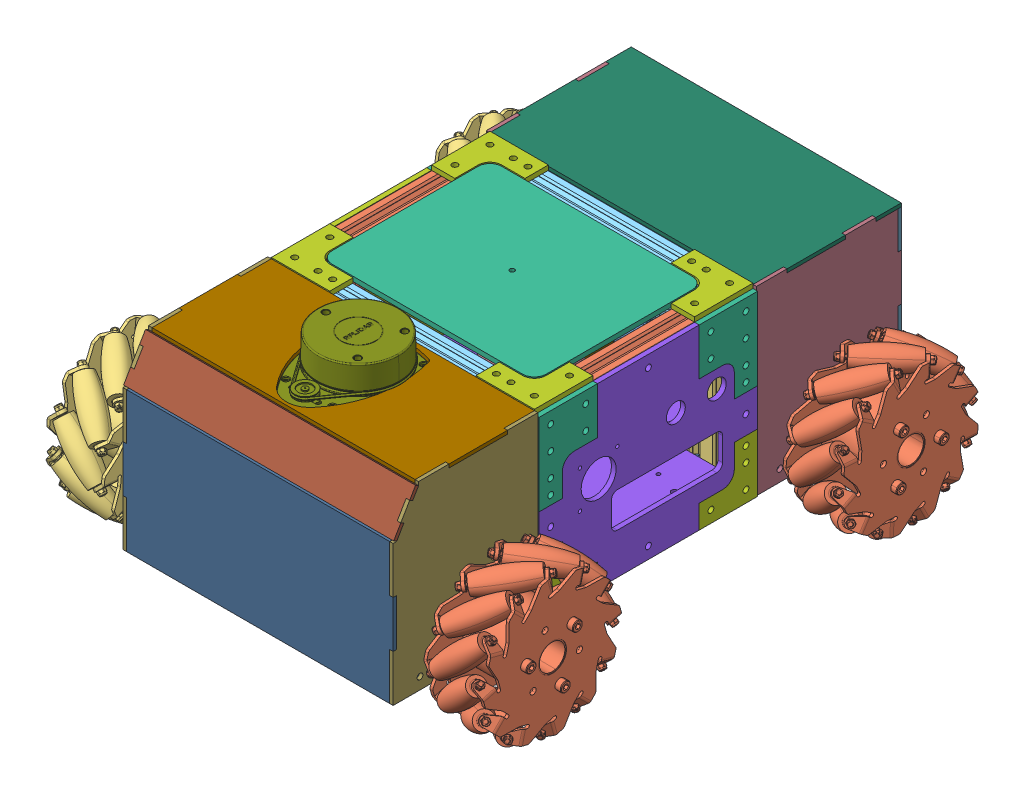
SolidWorks assembly Full assembly, configuration Default. Lengths in mm.
Overall size (385.7 231.43 493.49).
90 component instances, 33 part files, 42 mates.
Components (placement in the parent):
- Main Aluminum Chassis-1: Main Aluminum Chassis [Default] at (67.5984 -599.2977 -854.162) size (233 156 428.62)
  - bottom rod-1: bottom rod [Default] at (448.0592 609.2977 285.782) x (0 1 0) z (0 0 1) size (20 40 428.62)
  - bottom rod-2: bottom rod [Default] at (633.0592 609.2977 285.782) x (0 -1 0) z (0 0 1) size (20 40 428.62)
  - Top Rod-3: Top Rod [Default] at (643.0592 731.2977 164.972) size (20 40 187)
  - Top Rod-4: Top Rod [Default] at (438.0592 731.2977 164.972) size (20 40 187)
  - 147 mm.step-1: 147 mm.step [Default] at (448.0592 1619.2977 1154.972) x (0 0 1) z (0 -1 0) size (20 40 92)
  - 147 mm.step-2: 147 mm.step [Default] at (448.0592 1619.2977 987.972) x (0 0 -1) z (0 -1 0) size (20 40 92)
  - 147 mm.step-3: 147 mm.step [Default] at (633.0592 1619.2977 1154.972) x (0 0 1) z (0 -1 0) size (20 40 92)
  - 147 mm.step-4: 147 mm.step [Default] at (633.0592 -288.7023 987.972) x (0 0 1) z (0 1 0) size (20 40 92)
  - 300 mm rod.step-1: 300 mm rod.step [Default] at (-386.9408 609.2977 1144.972) x (0 -1 0) z (1 0 0) size (20 40 145)
  - 300 mm rod.step-2: 300 mm rod.step [Default] at (-386.9408 609.2977 997.972) x (0 1 0) z (1 0 0) size (20 40 145)
  - 320 mm rod.step-3: 320 mm rod.step [Default] at (-366.9408 731.2977 1154.972) x (0 0 -1) z (1 0 0) size (20 40 185)
  - 320 mm rod.step-4: 320 mm rod.step [Default] at (-366.9408 731.2977 987.972) x (0 0 -1) z (1 0 0) size (20 40 185)
  - aluminum support-3: aluminum support [Default] at (424.0592 721.2977 997.972) x (0 0 1) z (1 0 0) size (50 70 4)
  - aluminum support-4: aluminum support [Default] at (428.0592 721.2977 1144.972) x (0 0 -1) z (-1 0 0) size (50 70 4)
  - aluminum support-7: aluminum support [Default] at (657.0592 721.2977 1144.972) x (0 0 -1) z (-1 0 0) size (50 70 4)
  - aluminum support-8: aluminum support [Default] at (653.0592 721.2977 997.972) x (0 0 1) z (1 0 0) size (50 70 4)
  - aluminum support - 3-1: aluminum support - 3 [Default] at (424.0592 609.2977 1144.972) x (0 0 -1) z (1 0 0) size (50 50 4)
  - aluminum support - 3-2: aluminum support - 3 [Default] at (428.0592 609.2977 997.972) x (0 0 1) z (-1 0 0) size (50 50 4)
  - aluminum support - 3-4: aluminum support - 3 [Default] at (657.0592 609.2977 997.972) x (0 0 1) z (-1 0 0) size (50 50 4)
  - aluminum support - 3-5: aluminum support - 3 [Default] at (657.0592 619.2977 1154.972) x (0 1 0) z (-1 0 0) size (50 50 4)
  - aluminum support - 3-6: aluminum support - 3 [Default] at (438.0592 751.2977 997.972) x (0 0 1) z (0 1 0) size (50 50 4)
  - aluminum support - 3-7: aluminum support - 3 [Default] at (438.0592 755.2977 1144.972) x (0 0 -1) z (0 -1 0) size (50 50 4)
  - aluminum support - 3-8: aluminum support - 3 [Default] at (643.0592 755.2977 997.972) x (0 0 1) z (0 -1 0) size (50 50 4)
  - aluminum support - 3-9: aluminum support - 3 [Default] at (643.0592 751.2977 1144.972) x (0 0 -1) z (0 1 0) size (50 50 4)
- Base plate and body-1: Base plate and body [Default] at (447.923 -292.9651 -602.3042) size (385.7 226 477.05) (flexible)
  - Base Plate-1: Base Plate [Default] at (160.2346 317.9651 819.6142) x (1 0 0) z (0 -1 0) size (225 428.62 5)
  - Motor bracket-1: Motor bracket [Default] at (105.7346 317.9651 702.6142) x (0 0 -1) z (1 0 0) size (40 50 43)
  - Motor bracket-4: Motor bracket [Default] at (214.7346 317.9651 629.9942) x (0 0 1) z (-1 0 0) size (40 50 43)
  - planetary motor-1: planetary motor [Default] at (210.7346 347.9651 702.6142) x (0 1 0) z (0 0 1) size (38.5 150.5 38.49)
  - planetary motor-3: planetary motor [Default] at (109.7346 347.9651 629.9942) x (0 -0.707107 -0.707107) z (0 -0.707107 0.707107) size (38.5 150.5 38.49)
  - Pillow Block P08-3: Pillow Block P08 [Default] at (57.7346 332.9651 666.3042) x (0 0 1) z (-1 0 0) size (55 39.88 14.5)
  - Pillow Block P08-18: Pillow Block P08 [Default] at (262.7346 332.9651 666.3042) x (0 0 -1) z (1 0 0) size (55 39.88 14.5)
  - Pillow Block P08-5: Pillow Block P08 [Default] at (262.7346 332.9651 972.9242) x (0 0 -1) z (1 0 0) size (55 39.88 14.5)
  - planetary motor-4: planetary motor [Default] at (109.7346 347.9651 1009.2342) x (0 -0.707107 0.707107) z (0 0.707107 0.707107) size (38.5 150.5 38.49)
  - Motor bracket-3: Motor bracket [Default] at (214.7346 317.9651 1009.2342) x (0 0 1) z (-1 0 0) size (40 50 43)
  - wheel axe-4: wheel axe [Default] at (247.7846 332.9651 972.9242) x (0 0.812189 -0.583394) z (1 0 0) size (8 8 73)
  - wheel axe-1: wheel axe [Default] at (72.6846 332.9651 666.3042) x (0 -0.250872 -0.96802) z (-1 0 0) size (8 8 73)
  - wheel axe-2: wheel axe [Default] at (247.7846 332.9651 666.3042) x (0 -0.625718 0.780049) z (1 0 0) size (8 8 73)
  - wheel axe-8: wheel axe [Default] at (72.6846 332.9651 972.9242) x (0 -0.849321 0.527877) z (-1 0 0) size (8 8 73)
  - Motor bracket-8: Motor bracket [Default] at (105.7346 317.9651 936.6142) x (0 0 -1) z (1 0 0) size (40 50 43)
  - planetary motor-8: planetary motor [Default] at (210.7346 347.9651 936.6142) x (0 -0.707107 -0.707107) z (0 0.707107 -0.707107) size (38.5 150.5 38.49)
  - Pillow Block P08-9: Pillow Block P08 [Default] at (57.7346 332.9651 972.9242) x (0 0 1) z (-1 0 0) size (55 39.88 14.5)
  - MD13S-8: MD13S [Default] at (194.4964 317.9651 889.1442) x (-1 0 0) z (0 0 -1) size (60.96 12.27 33.02)
  - Pillow Block P08-16: Pillow Block P08 [Default] at (242.7346 332.9651 666.3042) x (0 0 1) z (-1 0 0) size (55 39.88 14.5)
  - Pillow Block P08-15: Pillow Block P08 [Default] at (77.7346 332.9651 666.3042) x (0 0 -1) z (1 0 0) size (55 39.88 14.5)
  - Pillow Block P08-14: Pillow Block P08 [Default] at (242.7346 332.9651 972.9242) x (0 0 1) z (-1 0 0) size (55 39.88 14.5)
  - Pillow Block P08-17: Pillow Block P08 [Default] at (77.7346 332.9651 972.9242) x (0 0 -1) z (1 0 0) size (55 39.88 14.5)
  - mid level plate-1: mid level plate [Default] at (160.2346 409.9651 964.1142) size (225 3 100)
  - 82mm spacer-3: 82mm spacer [Default] at (57.7346 317.9651 1004.1142) size (5.37 92 4.65)
  - 82mm spacer-2: 82mm spacer [Default] at (262.7346 317.9651 1004.1142) x (0.536786 0 -0.843719) z (0.843719 0 0.536786) size (5.37 92 4.65)
  - 82mm spacer-4: 82mm spacer [Default] at (262.7346 317.9651 924.1142) x (0.814654 0 -0.579948) z (0.579948 0 0.814654) size (5.37 92 4.65)
  - 82mm spacer-5: 82mm spacer [Default] at (57.7346 317.9651 924.1142) size (5.37 92 4.65)
  - RPLIDAR A1 DevKit.igs-1: RPLIDAR A1 DevKit.igs [Default] at (147.0194 421.8691 1020.526) x (-0.001508 0 0.999999) z (-0.999999 0 -0.001508) size (97.53 56.6 71.78)
  - GT2_20Teeth_Pully-1: GT2_20Teeth_Pully [Default] at (76.1346 347.9651 702.6142) x (0 0.998416 0.056263) z (0 -0.056263 0.998416) size (16 16 16)
  - GT2_20Teeth_Pully-2: GT2_20Teeth_Pully [Default] at (65.3346 332.9651 666.3042) x (0 0 -1) z (0 -1 0) size (16 16 16)
  - GT2_20Teeth_Pully-3: GT2_20Teeth_Pully [Default] at (255.1346 332.9651 666.3042) x (0 0.713065 -0.701097) z (0 0.701097 0.713065) size (16 16 16)
  - GT2_20Teeth_Pully-4: GT2_20Teeth_Pully [Default] at (244.3346 347.9651 629.9942) x (0 1 0) z (0 0 -1) size (16 16 16)
  - GT2_20Teeth_Pully-5: GT2_20Teeth_Pully [Default] at (76.1346 347.9651 936.6142) x (0 1 0) z (0 0 1) size (16 16 16)
  - GT2_20Teeth_Pully-6: GT2_20Teeth_Pully [Default] at (65.3346 332.9651 972.9242) x (0 0.950914 -0.309455) z (0 -0.309455 -0.950914) size (16 16 16)
  - GT2_20Teeth_Pully-7: GT2_20Teeth_Pully [Default] at (244.3346 347.9651 1009.2342) x (0 0.247004 -0.969014) z (0 -0.969014 -0.247004) size (16 16 16)
  - GT2_20Teeth_Pully-8: GT2_20Teeth_Pully [Default] at (255.1346 332.9651 972.9242) x (0 1 0) z (0 0 1) size (16 16 16)
  - 70mm spacer-8: 70mm spacer [Default] at (262.7346 317.9651 635.1142) size (5.37 60 4.65)
  - 70mm spacer-7: 70mm spacer [Default] at (262.7346 317.9651 715.1142) size (5.37 60 4.65)
  - 70mm spacer-10: 70mm spacer [Default] at (57.7346 317.9651 715.1142) size (5.37 60 4.65)
  - 70mm spacer-9: 70mm spacer [Default] at (57.7346 317.9651 635.1142) size (5.37 60 4.65)
  - mid level plate-2: mid level plate [Default] at (160.2346 377.9651 675.1142) size (225 3 100)
  - motor support-1: motor support [Default] at (148.2346 347.9651 1009.2342) x (0 0 -1) z (1 0 0) size (45 59.2 20)
  - motor support-2: motor support [Default] at (172.2346 347.9651 936.6142) x (0 0 1) z (-1 0 0) size (45 59.2 20)
  - motor support-3: motor support [Default] at (172.2346 347.9651 702.6142) x (0 0 1) z (-1 0 0) size (45 59.2 20)
  - motor support-4: motor support [Default] at (168.2346 347.9651 629.9942) x (0 0 1) z (-1 0 0) size (45 59.2 20)
  - Mecanum wheel 127mm L-1: Mecanum wheel 127mm L [Default] at (183.1488 350.9477 968.6567) x (0 0.968231 -0.250058) z (1 0 0) size (136.87 136.87 82.4)
  - Mecanum wheel 127mm L-2: Mecanum wheel 127mm L [Default] at (183.1488 342.8503 681.9205) x (0 0.551425 0.834225) z (1 0 0) size (136.87 136.87 82.4)
  - Mecanum wheel 127mm R-1: Mecanum wheel 127mm R [Default] at (137.8056 298.0555 930.8075) x (0 -0.579875 -0.814705) z (-1 0 0) size (132 132 82.4)
  - Mecanum wheel 127mm R-2: Mecanum wheel 127mm R [Default] at (137.8056 357.8029 715.0442) x (0 0.387362 0.921928) z (-1 0 0) size (132 132 82.4)
- Linear_actuator_2_inches-1: Linear_actuator_2_inches [Default] at (628.1601 25 236.995) x (-1 0 0) z (0 0 -1) size (183 131 145) (flexible)
  - linear_actuator_2inch_stroke-1: linear_actuator_2inch_stroke [Default] at (40.005 8.509 0) x (-1 0 0) z (0 1 0) size (40 75.27 111.27)
  - shaft_2inches-2: shaft_2inches [Default] at (0 47.2006 39.37) x (1 0 0) z (0 1 0) size (19.56 19.56 79.8)
  - lifting mechanism - top plate-1: lifting mechanism - top plate [Default] at (20.0025 126.999 19.685) x (0 0 -1) z (1 0 0) size (145 4 183)
- side plates - 1-1: side plates - 1 [Default] at (495.6576 66 217.31) x (0 0 1) z (-1 0 0) size (187 152 4)
- side plates-2: side plates [Default] at (720.6576 66 217.31) x (0 0 -1) z (1 0 0) size (187 152 4)
- skin front top-1: skin front top [Default] at (608.0003 152 360.3941) x (1 0 0) z (0 1 0) size (231 102 3.02)
- skin front-1: skin front [Default] at (608.1576 60 431.62) size (231 120 3)
- skin front top slide-1: skin front top slide [Default] at (609.1576 135.9708 422.2322) x (1 0 0) z (0 0.506749 0.862093) size (231 36.98 3)
- skin front side1-1: skin front side1 [Default] at (720.6576 76.044 371.18) x (0 0 -1) z (1 0 0) size (123.81 155 3)
- skin front side1-2: skin front side1 [Default] at (492.6576 76.044 371.18) x (0 0 -1) z (1 0 0) size (123.81 155 3)
- skin back side-3: skin back side [Default] at (723.6576 76.044 63.44) x (0 0 1) z (-1 0 0) size (123.81 155 3)
- skin back side-4: skin back side [Default] at (495.6576 76.044 63.44) x (0 0 1) z (-1 0 0) size (123.81 155 3)
- skin Back-1: skin Back [Default] at (608.1576 60 0) size (231 152 3)
- skin back top-1: skin back top [Default] at (608.0003 155 74.2259) x (1 0 0) z (0 -1 0) size (231 123.81 3)
Mates (geometry in assembly coordinates):
- Distance1: distance = 1 mm anti-aligned: plane of Main Aluminum Chassis-1/147 mm.step-1 through (535.6576 20 300.81) normal (1 0 0); plane of Base plate and body-1/Base Plate-1 through (536.6576 20 311.81) normal (-1 0 0)
- Distance2: distance = 1 mm anti-aligned: plane of Base plate and body-1/Base Plate-1 through (495.6576 20 289.81) normal (0 0 1); plane of Main Aluminum Chassis-1/147 mm.step-1 through (515.6576 20 290.81) normal (0 0 -1)
- Coincident3: coincident anti-aligned: plane of Main Aluminum Chassis-1/bottom rod-1 through (515.6576 20 431.62) normal (0 1 0); plane of Base plate and body-1/Base Plate-1 through (608.1576 20 217.31) normal (0 -1 0)
- Distance6: distance = 1 mm anti-aligned: plane of Linear_actuator_2_inches-1/lifting mechanism - top plate-1 through (699.6576 145.999 154.81) normal (1 0 0); plane of Main Aluminum Chassis-1/aluminum support - 3-9 through (700.6576 156 260.81) normal (-1 0 0)
- Distance7: distance = 1 mm anti-aligned: plane of Linear_actuator_2_inches-1/lifting mechanism - top plate-1 through (689.6576 145.999 144.81) normal (0 0 -1); plane of Main Aluminum Chassis-1/aluminum support - 3-8 through (670.6576 152 143.81) normal (0 0 1)
- Parallel6: parallel anti-aligned: plane of Main Aluminum Chassis-1/300 mm rod.step-1 through (680.6576 10 270.81) normal (0 0 -1); plane of Linear_actuator_2_inches-1/linear_actuator_2inch_stroke-1 through (588.1551 42.018 236.995) normal (0 0 1)
- Coincident12: coincident anti-aligned: plane of Base plate and body-1/Base Plate-1 through (608.1576 25 217.31) normal (0 1 0); plane of Linear_actuator_2_inches-1/linear_actuator_2inch_stroke-1 through (608.1576 25 181.9913) normal (0 -1 0)
- Coincident26: coincident anti-aligned: plane of Main Aluminum Chassis-1/bottom rod-1 through (495.6576 10 431.62) normal (-1 0 0); plane of side plates - 1-1 through (495.6576 30 153.81) normal (1 0 0)
- Coincident27: coincident anti-aligned: plane of Main Aluminum Chassis-1/aluminum support-3 through (495.6576 82 123.81) normal (0 -1 0); plane of side plates - 1-1 through (491.6576 82 143.81) normal (0 1 0)
- Coincident28: coincident aligned: plane of Main Aluminum Chassis-1/aluminum support-3 through (495.6576 152 123.81) normal (0 0 -1); plane of side plates - 1-1 through (491.6576 82 123.81) normal (0 0 -1)
- Coincident64: coincident aligned: plane of skin front top-1 through (492.6576 155 336.81) normal (-1 0 0); plane of skin front side1-2 through (492.6576 40 370.62) normal (-1 0 0)
- Coincident65: coincident anti-aligned: plane of skin front top-1 through (492.6576 155 386.81) normal (0 0 1); plane of skin front side1-2 through (495.6576 155 386.81) normal (0 0 -1)
- Coincident66: coincident aligned: plane of skin front top-1 through (608.0003 155 360.3941) normal (0 1 0); plane of skin front side1-2 through (495.6576 155 412.81) normal (0 1 0)
- Coincident67: coincident anti-aligned: plane of skin front top slide-1 through (609.1576 135.9708 422.2322) normal (0 -0.506749 -0.862093); plane of skin front side1-2 through (495.6576 152 412.81) normal (0 0.506749 0.862093)
- Coincident68: coincident aligned: plane of skin front top slide-1 through (492.6576 153.5202 415.3963) normal (-1 0 0); plane of skin front side1-2 through (492.6576 40 370.62) normal (-1 0 0)
- Coincident69: coincident anti-aligned: plane of skin front top slide-1 through (492.6576 131.9679 428.065) normal (0 0.862093 -0.506749); plane of skin front side1-2 through (495.6576 130.4477 425.4787) normal (0 -0.862093 0.506749)
- Coincident70: coincident anti-aligned: plane of skin front-1 through (608.1576 60 431.62) normal (0 0 -1); plane of skin front side1-2 through (495.6576 80 431.62) normal (0 0 1)
- Coincident71: coincident anti-aligned: plane of skin front-1 through (495.6576 80 434.62) normal (0 1 0); plane of skin front side1-2 through (495.6576 80 434.62) normal (0 -1 0)
- Coincident72: coincident aligned: plane of skin front-1 through (492.6576 80 434.62) normal (-1 0 0); plane of skin front side1-2 through (492.6576 40 370.62) normal (-1 0 0)
- Coincident73: coincident anti-aligned: plane of Main Aluminum Chassis-1/bottom rod-1 through (515.6576 10 431.62) normal (0 0 1); plane of skin front-1 through (608.1576 60 431.62) normal (0 0 -1)
- Coincident74: coincident aligned: plane of Main Aluminum Chassis-1/bottom rod-1 through (515.6576 0 431.62) normal (0 -1 0); plane of skin front-1 through (495.6576 0 434.62) normal (0 -1 0)
- Coincident75: coincident anti-aligned: plane of Main Aluminum Chassis-1/bottom rod-1 through (495.6576 10 431.62) normal (-1 0 0); plane of skin front side1-2 through (495.6576 40 370.62) normal (1 0 0)
- Coincident76: coincident aligned: plane of skin front top-1 through (723.6576 155 386.81) normal (1 0 0); plane of skin front side1-1 through (723.6576 40 370.62) normal (1 0 0)
- Coincident77: coincident aligned: plane of skin front-1 through (495.6576 0 434.62) normal (0 -1 0); plane of skin front side1-1 through (723.6576 0 386.5043) normal (0 -1 0)
- Coincident78: coincident aligned: plane of skin front-1 through (608.1576 60 434.62) normal (0 0 1); plane of skin front side1-1 through (723.6576 0 434.62) normal (0 0 1)
- Coincident79: coincident anti-aligned: plane of Main Aluminum Chassis-1/bottom rod-1 through (495.6576 10 431.62) normal (-1 0 0); plane of skin back side-4 through (495.6576 40 64) normal (1 0 0)
- Coincident81: coincident aligned: plane of Main Aluminum Chassis-1/bottom rod-1 through (515.6576 0 431.62) normal (0 -1 0); plane of skin back side-4 through (492.6576 0 48.1157) normal (0 -1 0)
- Coincident82: coincident anti-aligned: plane of Main Aluminum Chassis-1/bottom rod-2 through (720.6576 10 431.62) normal (1 0 0); plane of skin back side-3 through (720.6576 40 64) normal (-1 0 0)
- Coincident83: coincident aligned: plane of Main Aluminum Chassis-1/bottom rod-2 through (700.6576 0 431.62) normal (0 -1 0); plane of skin back side-3 through (720.6576 0 48.1157) normal (0 -1 0)
- Coincident84: coincident anti-aligned: plane of Main Aluminum Chassis-1/aluminum support-8 through (724.6576 152 123.81) normal (0 0 -1); plane of skin back side-3 through (720.6576 152 123.81) normal (0 0 1)
- Coincident85: coincident aligned: plane of Main Aluminum Chassis-1/bottom rod-1 through (515.6576 10 3) normal (0 0 -1); plane of skin back side-4 through (492.6576 80 3) normal (0 0 -1)
- Coincident86: coincident aligned: plane of skin back side-3 through (720.6576 120 0) normal (0 0 -1); plane of skin Back-1 through (608.1576 60 0) normal (0 0 -1)
- Coincident87: coincident aligned: plane of skin back side-3 through (723.6576 40 64) normal (1 0 0); plane of skin Back-1 through (723.6576 80 3) normal (1 0 0)
- Coincident88: coincident anti-aligned: plane of skin back side-3 through (720.6576 80 0) normal (0 -1 0); plane of skin Back-1 through (720.6576 80 3) normal (0 1 0)
- Coincident90: coincident anti-aligned: plane of skin back side-3 through (720.6576 152 97.81) normal (0 1 0); plane of skin back top-1 through (608.0003 152 74.2259) normal (0 -1 0)
- Coincident91: coincident anti-aligned: plane of skin back side-4 through (492.6576 155 97.81) normal (0 0 -1); plane of skin back top-1 through (495.6576 152 97.81) normal (0 0 1)
- Coincident92: coincident anti-aligned: plane of skin back side-4 through (495.6576 40 64) normal (1 0 0); plane of skin back top-1 through (495.6576 152 47.81) normal (-1 0 0)
- Coincident94: coincident anti-aligned: plane of Main Aluminum Chassis-1/Top Rod-3 through (720.6576 132 310.81) normal (1 0 0); plane of side plates-2 through (720.6576 30 280.81) normal (-1 0 0)
- Coincident95: coincident anti-aligned: plane of Main Aluminum Chassis-1/aluminum support-7 through (720.6576 152 260.81) normal (0 0 -1); plane of side plates-2 through (724.6576 152 260.81) normal (0 0 1)
- Coincident96: coincident aligned: plane of Main Aluminum Chassis-1/aluminum support - 3-5 through (720.6576 0 310.81) normal (0 -1 0); plane of side plates-2 through (724.6576 0 260.81) normal (0 -1 0)
- Coincident97: coincident anti-aligned: plane of Main Aluminum Chassis-1/300 mm rod.step-1 through (680.6576 0 290.81) normal (0 -1 0)
- Coincident98: coincident anti-aligned: plane of skin Back-1 through (608.1576 60 0) normal (0 0 -1)
